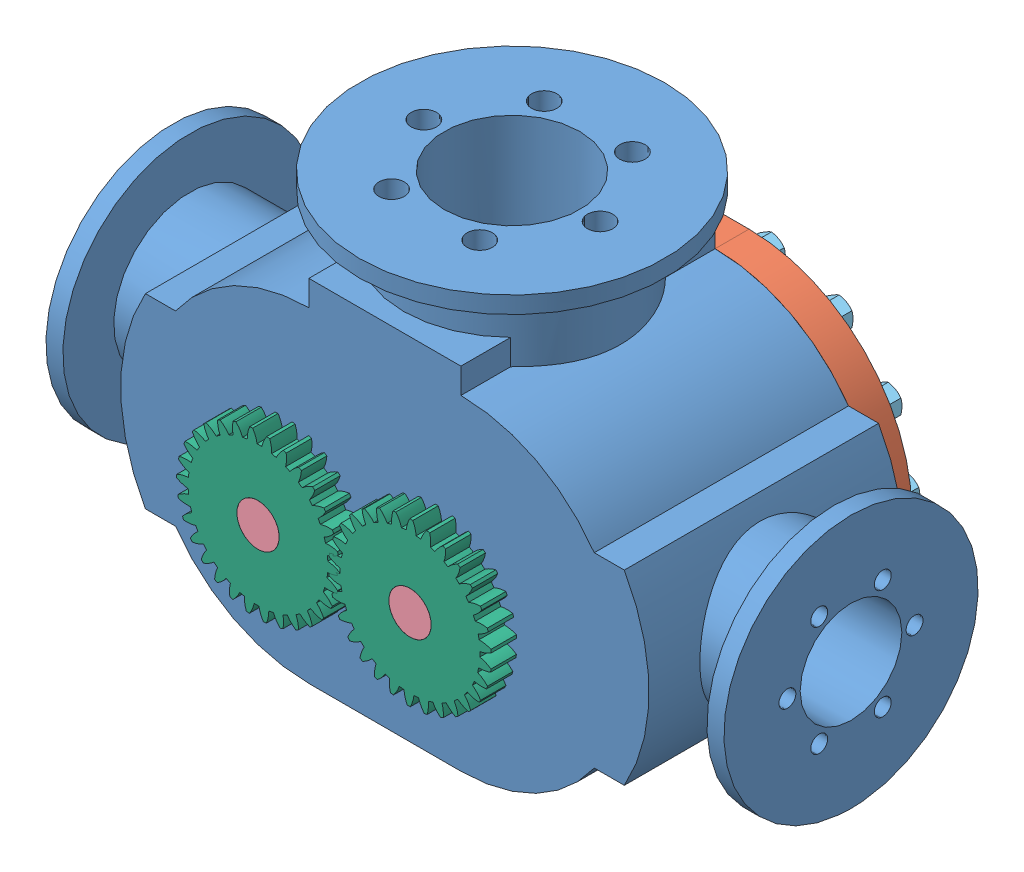
SolidWorks assembly Assem1 PROJECT, configuration Default. Lengths in mm.
Overall size (400 247 215).
24 component instances, 6 part files, 51 mates.
Components (placement in the parent):
- PROJECT PART 1-3: PROJECT PART 1 [Default] at (85.8404 182.767 240.8257) size (400 247 180)
- PROJECT PART 2-2: PROJECT PART 2 [Default] at (85.8404 182.767 220.8257) size (281.69 192 20)
- PROJECT PART 3-2: PROJECT PART 3 [Default] at (175.5304 182.767 230.8257) x (-0.818223 -0.5749 0) z (0 0 1) size (106 106 150)
- PROJECT PART 4-4: PROJECT PART 4 [Default] at (175.5304 182.767 420.8257) x (0.799608 -0.600523 0) z (0 0 -1) size (27.41 28.82 215)
- PROJECT PART 4-5: PROJECT PART 4 [Default] at (85.8404 182.767 420.8257) x (0.083921 -0.996472 0) z (0 0 -1) size (27.41 28.82 215)
- PROJECT PART 3-3: PROJECT PART 3 [Default] at (85.8404 182.767 230.8257) x (-0.083921 0.996472 0) z (0 0 1) size (106 106 150)
- heavy hex flange screw_am-5: heavy hex flange screw_am [B18.2.3.9M - Heavy hex flange screw, M10 x 1.5 x 50 --26N] at (179.0389 265.5677 210.4257) x (0 0 1) z (-1 0 0) size (60.4 22.3 22.3)
- heavy hex flange screw_am-6: heavy hex flange screw_am [B18.2.3.9M - Heavy hex flange screw, M10 x 1.5 x 50 --26N] at (130.6854 265.642 210.4257) x (0 0 1) z (-1 0 0) size (60.4 22.3 22.3)
- heavy hex flange screw_am-7: heavy hex flange screw_am [B18.2.3.9M - Heavy hex flange screw, M10 x 1.5 x 50 --26N] at (82.3319 265.5677 210.4257) x (0 0 1) z (-1 0 0) size (60.4 22.3 22.3)
- heavy hex flange screw_am-8: heavy hex flange screw_am [B18.2.3.9M - Heavy hex flange screw, M10 x 1.5 x 50 --26N] at (42.3934 253.3405 210.4257) x (0 0 1) z (-1 0 0) size (60.4 22.3 22.3)
- heavy hex flange screw_am-9: heavy hex flange screw_am [B18.2.3.9M - Heavy hex flange screw, M10 x 1.5 x 50 --26N] at (13.4907 223.1873 210.4257) x (0 0 1) z (-1 0 0) size (60.4 22.3 22.3)
- heavy hex flange screw_am-10: heavy hex flange screw_am [B18.2.3.9M - Heavy hex flange screw, M10 x 1.5 x 50 --26N] at (2.9654 182.767 210.4257) x (0 0 1) z (-1 0 0) size (60.4 22.3 22.3)
- heavy hex flange screw_am-11: heavy hex flange screw_am [B18.2.3.9M - Heavy hex flange screw, M10 x 1.5 x 50 --26N] at (13.4907 142.3467 210.4257) x (0 0 1) z (-1 0 0) size (60.4 22.3 22.3)
- heavy hex flange screw_am-12: heavy hex flange screw_am [B18.2.3.9M - Heavy hex flange screw, M10 x 1.5 x 50 --26N] at (42.3934 112.1934 210.4257) x (0 0 1) z (-1 0 0) size (60.4 22.3 22.3)
- heavy hex flange screw_am-14: heavy hex flange screw_am [B18.2.3.9M - Heavy hex flange screw, M10 x 1.5 x 50 --26N] at (130.6854 99.892 210.4257) x (0 0 1) z (-1 0 0) size (60.4 22.3 22.3)
- heavy hex flange screw_am-15: heavy hex flange screw_am [B18.2.3.9M - Heavy hex flange screw, M10 x 1.5 x 50 --26N] at (179.0389 99.9663 210.4257) x (0 0 1) z (-1 0 0) size (60.4 22.3 22.3)
- heavy hex flange screw_am-16: heavy hex flange screw_am [B18.2.3.9M - Heavy hex flange screw, M10 x 1.5 x 50 --26N] at (218.9773 112.1934 210.4257) x (0 0 1) z (-1 0 0) size (60.4 22.3 22.3)
- heavy hex flange screw_am-17: heavy hex flange screw_am [B18.2.3.9M - Heavy hex flange screw, M10 x 1.5 x 50 --26N] at (247.88 142.3467 210.4257) x (0 0 1) z (-1 0 0) size (60.4 22.3 22.3)
- heavy hex flange screw_am-18: heavy hex flange screw_am [B18.2.3.9M - Heavy hex flange screw, M10 x 1.5 x 50 --26N] at (258.4054 182.767 210.4257) x (0 0 1) z (-1 0 0) size (60.4 22.3 22.3)
- heavy hex flange screw_am-19: heavy hex flange screw_am [B18.2.3.9M - Heavy hex flange screw, M10 x 1.5 x 50 --26N] at (247.88 223.1873 210.4257) x (0 0 1) z (-1 0 0) size (60.4 22.3 22.3)
- heavy hex flange screw_am-20: heavy hex flange screw_am [B18.2.3.9M - Heavy hex flange screw, M10 x 1.5 x 50 --26N] at (218.9773 253.3405 210.4257) x (0 0 1) z (-1 0 0) size (60.4 22.3 22.3)
- heavy hex flange screw_am-21: heavy hex flange screw_am [B18.2.3.9M - Heavy hex flange screw, M10 x 1.5 x 50 --26N] at (82.3319 99.9663 210.4257) x (0 0 1) z (-1 0 0) size (60.4 22.3 22.3)
- spur gear_am-8: spur gear_am [Metric - Spur gear 3M 30T 20PA 15FW ---S30N75H50L20N] at (85.8404 182.767 420.8257) x (0 0 -1) z (0.083921 -0.996472 0) size (15 95.64 96)
- spur gear_am-9: spur gear_am [Metric - Spur gear 3M 30T 20PA 15FW ---S30N75H50L20N] at (175.5304 182.767 420.8257) x (0 0 -1) z (0.600523 0.799608 0) size (15 95.64 96)
Mates (geometry in assembly coordinates):
- Concentric3: concentric anti-aligned: cylinder of PROJECT PART 1-3 through (85.8404 182.767 520.8257) axis (0 0 -1) radius 12.5; cylinder of PROJECT PART 4-5 through (85.8404 182.767 205.8257) axis (0 0 1) radius 12.5
- Distance1: distance = 30 mm aligned: plane of PROJECT PART 1-3 through (85.8404 182.767 390.8257) normal (0 0 1); plane of PROJECT PART 4-5 through (85.8404 182.767 420.8257) normal (0 0 1)
- Concentric5: concentric anti-aligned: cylinder of PROJECT PART 1-3 through (175.5304 182.767 520.8257) axis (0 0 -1) radius 12.5; cylinder of PROJECT PART 4-4 through (175.5304 182.767 205.8257) axis (0 0 1) radius 12.5
- Distance3: distance = 30 mm aligned: plane of PROJECT PART 4-4 through (175.5304 182.767 420.8257) normal (0 0 1); plane of PROJECT PART 1-3 through (85.8404 182.767 390.8257) normal (0 0 1)
- Concentric6: concentric anti-aligned: cylinder of PROJECT PART 3-2 through (175.5304 182.767 380.8257) axis (0 0 -1) radius 12.5; cylinder of PROJECT PART 4-4 through (175.5304 182.767 205.8257) axis (0 0 1) radius 12.5
- Coincident9: coincident anti-aligned: plane of PROJECT PART 3-2 through (185.1273 178.0607 380.8257) normal (-0.600523 -0.799608 0); plane of PROJECT PART 4-4 through (176.7314 184.3662 230.8257) normal (0.600523 0.799608 0)
- Coincident10: coincident aligned: plane of PROJECT PART 3-2 through (175.5304 182.767 230.8257) normal (0 0 -1); plane of PROJECT PART 4-4 through (175.5304 182.767 230.8257) normal (0 0 -1)
- Concentric7: concentric anti-aligned: cylinder of PROJECT PART 4-5 through (85.8404 182.767 205.8257) axis (0 0 1) radius 12.5; cylinder of PROJECT PART 3-3 through (85.8404 182.767 380.8257) axis (0 0 -1) radius 12.5
- Coincident12: coincident anti-aligned: plane of PROJECT PART 4-5 through (86.6158 180.9234 230.8257) normal (0.38774 -0.921769 0); plane of PROJECT PART 3-3 through (76.9373 176.8522 380.8257) normal (-0.38774 0.921769 0)
- Coincident13: coincident aligned: plane of PROJECT PART 4-5 through (85.8404 182.767 230.8257) normal (0 0 -1); plane of PROJECT PART 3-3 through (85.8404 182.767 230.8257) normal (0 0 -1)
- GearMate3: gear = 25 : 25 mm: cylinder of PROJECT PART 4-4 through (175.5304 182.767 205.8257) axis (0 0 1) radius 12.5; cylinder of PROJECT PART 4-5 through (85.8404 182.767 205.8257) axis (0 0 1) radius 12.5
- Coincident15: coincident aligned: circle of PROJECT PART 2-2; cylinder of PROJECT PART 4-4 through (175.5304 182.767 205.8257) axis (0 0 1) radius 12.5
- Coincident16: coincident anti-aligned: plane of PROJECT PART 1-3 through (85.8404 182.767 240.8257) normal (0 0 -1); plane of PROJECT PART 2-2 through (85.8404 182.767 240.8257) normal (0 0 1)
- Concentric16: concentric anti-aligned: cylinder of PROJECT PART 2-2 through (179.0389 265.5677 220.8257) axis (0 0 1) radius 5; cylinder of heavy hex flange screw_am-5 through (179.0389 265.5677 210.4257) axis (0 0 -1) radius 5
- Coincident18: coincident anti-aligned: plane of PROJECT PART 2-2 through (85.8404 182.767 220.8257) normal (0 0 -1); plane of heavy hex flange screw_am-5 through (179.0389 274.2279 220.8257) normal (0 0 1)
- Concentric17: concentric anti-aligned: cylinder of PROJECT PART 2-2 through (130.6854 265.642 220.8257) axis (0 0 1) radius 5; cylinder of heavy hex flange screw_am-6 through (130.6854 265.642 210.4257) axis (0 0 -1) radius 5
- Coincident19: coincident anti-aligned: plane of PROJECT PART 2-2 through (85.8404 182.767 220.8257) normal (0 0 -1); plane of heavy hex flange screw_am-6 through (130.6854 274.3022 220.8257) normal (0 0 1)
- Concentric18: concentric anti-aligned: cylinder of PROJECT PART 2-2 through (82.3319 265.5677 220.8257) axis (0 0 1) radius 5; cylinder of heavy hex flange screw_am-7 through (82.3319 265.5677 210.4257) axis (0 0 -1) radius 5
- Coincident20: coincident anti-aligned: plane of PROJECT PART 2-2 through (85.8404 182.767 220.8257) normal (0 0 -1); plane of heavy hex flange screw_am-7 through (82.3319 274.2279 220.8257) normal (0 0 1)
- Concentric19: concentric anti-aligned: cylinder of PROJECT PART 2-2 through (42.3934 253.3405 220.8257) axis (0 0 1) radius 5; cylinder of heavy hex flange screw_am-8 through (42.3934 253.3405 210.4257) axis (0 0 -1) radius 5
- Coincident21: coincident anti-aligned: plane of PROJECT PART 2-2 through (85.8404 182.767 220.8257) normal (0 0 -1); plane of heavy hex flange screw_am-8 through (42.3934 262.0008 220.8257) normal (0 0 1)
- Concentric20: concentric anti-aligned: cylinder of PROJECT PART 2-2 through (13.4907 223.1873 220.8257) axis (0 0 1) radius 5; cylinder of heavy hex flange screw_am-9 through (13.4907 223.1873 210.4257) axis (0 0 -1) radius 5
- Coincident22: coincident anti-aligned: plane of PROJECT PART 2-2 through (85.8404 182.767 220.8257) normal (0 0 -1); plane of heavy hex flange screw_am-9 through (13.4907 231.8475 220.8257) normal (0 0 1)
- Concentric21: concentric anti-aligned: cylinder of PROJECT PART 2-2 through (2.9654 182.767 220.8257) axis (0 0 1) radius 5; cylinder of heavy hex flange screw_am-10 through (2.9654 182.767 210.4257) axis (0 0 -1) radius 5
- Coincident23: coincident anti-aligned: plane of PROJECT PART 2-2 through (85.8404 182.767 220.8257) normal (0 0 -1); plane of heavy hex flange screw_am-10 through (2.9654 191.4272 220.8257) normal (0 0 1)
- Concentric22: concentric anti-aligned: cylinder of PROJECT PART 2-2 through (13.4907 142.3467 220.8257) axis (0 0 1) radius 5; cylinder of heavy hex flange screw_am-11 through (13.4907 142.3467 210.4257) axis (0 0 -1) radius 5
- Coincident24: coincident anti-aligned: plane of PROJECT PART 2-2 through (85.8404 182.767 220.8257) normal (0 0 -1); plane of heavy hex flange screw_am-11 through (13.4907 151.0069 220.8257) normal (0 0 1)
- Concentric23: concentric anti-aligned: cylinder of PROJECT PART 2-2 through (42.3934 112.1934 220.8257) axis (0 0 1) radius 5; cylinder of heavy hex flange screw_am-12 through (42.3934 112.1934 210.4257) axis (0 0 -1) radius 5
- Coincident25: coincident anti-aligned: plane of PROJECT PART 2-2 through (85.8404 182.767 220.8257) normal (0 0 -1); plane of heavy hex flange screw_am-12 through (42.3934 120.8537 220.8257) normal (0 0 1)
- Concentric25: concentric anti-aligned: cylinder of PROJECT PART 2-2 through (130.6854 99.892 220.8257) axis (0 0 1) radius 5; cylinder of heavy hex flange screw_am-14 through (130.6854 99.892 210.4257) axis (0 0 -1) radius 5
- Coincident26: coincident anti-aligned: plane of PROJECT PART 2-2 through (85.8404 182.767 220.8257) normal (0 0 -1); plane of heavy hex flange screw_am-14 through (130.6854 108.5522 220.8257) normal (0 0 1)
- Concentric26: concentric anti-aligned: cylinder of PROJECT PART 2-2 through (179.0389 99.9663 220.8257) axis (0 0 1) radius 5; cylinder of heavy hex flange screw_am-15 through (179.0389 99.9663 210.4257) axis (0 0 -1) radius 5
- Coincident27: coincident anti-aligned: plane of PROJECT PART 2-2 through (85.8404 182.767 220.8257) normal (0 0 -1); plane of heavy hex flange screw_am-15 through (179.0389 108.6265 220.8257) normal (0 0 1)
- Concentric27: concentric anti-aligned: cylinder of PROJECT PART 2-2 through (218.9773 112.1934 220.8257) axis (0 0 1) radius 5; cylinder of heavy hex flange screw_am-16 through (218.9773 112.1934 210.4257) axis (0 0 -1) radius 5
- Coincident28: coincident anti-aligned: plane of PROJECT PART 2-2 through (85.8404 182.767 220.8257) normal (0 0 -1); plane of heavy hex flange screw_am-16 through (218.9773 120.8537 220.8257) normal (0 0 1)
- Concentric28: concentric anti-aligned: cylinder of PROJECT PART 2-2 through (247.88 142.3467 220.8257) axis (0 0 1) radius 5; cylinder of heavy hex flange screw_am-17 through (247.88 142.3467 210.4257) axis (0 0 -1) radius 5
- Coincident29: coincident anti-aligned: plane of PROJECT PART 2-2 through (85.8404 182.767 220.8257) normal (0 0 -1); plane of heavy hex flange screw_am-17 through (247.88 151.0069 220.8257) normal (0 0 1)
- Concentric29: concentric anti-aligned: cylinder of PROJECT PART 2-2 through (258.4054 182.767 220.8257) axis (0 0 1) radius 5; cylinder of heavy hex flange screw_am-18 through (258.4054 182.767 210.4257) axis (0 0 -1) radius 5
- Coincident30: coincident anti-aligned: plane of PROJECT PART 2-2 through (85.8404 182.767 220.8257) normal (0 0 -1); plane of heavy hex flange screw_am-18 through (258.4054 191.4272 220.8257) normal (0 0 1)
- Concentric30: concentric anti-aligned: cylinder of PROJECT PART 2-2 through (247.88 223.1873 220.8257) axis (0 0 1) radius 5; cylinder of heavy hex flange screw_am-19 through (247.88 223.1873 210.4257) axis (0 0 -1) radius 5
- Coincident31: coincident anti-aligned: plane of PROJECT PART 2-2 through (85.8404 182.767 220.8257) normal (0 0 -1); plane of heavy hex flange screw_am-19 through (247.88 231.8475 220.8257) normal (0 0 1)
- Concentric31: concentric anti-aligned: cylinder of PROJECT PART 2-2 through (218.9773 253.3405 220.8257) axis (0 0 1) radius 5; cylinder of heavy hex flange screw_am-20 through (218.9773 253.3405 210.4257) axis (0 0 -1) radius 5
- Coincident32: coincident anti-aligned: plane of PROJECT PART 2-2 through (85.8404 182.767 220.8257) normal (0 0 -1); plane of heavy hex flange screw_am-20 through (218.9773 262.0008 220.8257) normal (0 0 1)
- Concentric32: concentric anti-aligned: cylinder of PROJECT PART 2-2 through (82.3319 99.9663 220.8257) axis (0 0 1) radius 5; cylinder of heavy hex flange screw_am-21 through (82.3319 99.9663 210.4257) axis (0 0 -1) radius 5
- Coincident33: coincident anti-aligned: plane of PROJECT PART 2-2 through (85.8404 182.767 220.8257) normal (0 0 -1); plane of heavy hex flange screw_am-21 through (82.3319 108.6265 220.8257) normal (0 0 1)
- Concentric33: concentric aligned: cylinder of PROJECT PART 4-5 through (85.8404 182.767 205.8257) axis (0 0 1) radius 12.5; cylinder of spur gear_am-8 through (85.8404 182.767 370.8256) axis (0 0 1) radius 10
- Concentric34: concentric aligned: cylinder of PROJECT PART 4-4 through (175.5304 182.767 205.8257) axis (0 0 1) radius 12.5; cylinder of spur gear_am-9 through (175.5304 182.767 370.8256) axis (0 0 1) radius 10
- Coincident34: coincident aligned: plane of PROJECT PART 4-5 through (85.8404 182.767 420.8257) normal (0 0 1); plane of spur gear_am-8 through (85.8404 182.767 420.8257) normal (0 0 1)
- Coincident35: coincident aligned: plane of PROJECT PART 4-4 through (175.5304 182.767 420.8257) normal (0 0 1); plane of spur gear_am-9 through (175.5304 182.767 420.8257) normal (0 0 1)
- Coincident36: coincident anti-aligned: plane of PROJECT PART 4-5 through (85.8404 182.767 420.8257) normal (-0.996472 -0.083921 0); plane of spur gear_am-8 through (85.8404 182.767 420.8257) normal (0.996472 0.083921 0)
- Coincident37: coincident anti-aligned: plane of PROJECT PART 4-4 through (175.5304 182.767 420.8257) normal (0.799608 -0.600523 0); plane of spur gear_am-9 through (175.5304 182.767 420.8257) normal (-0.799608 0.600523 0)
